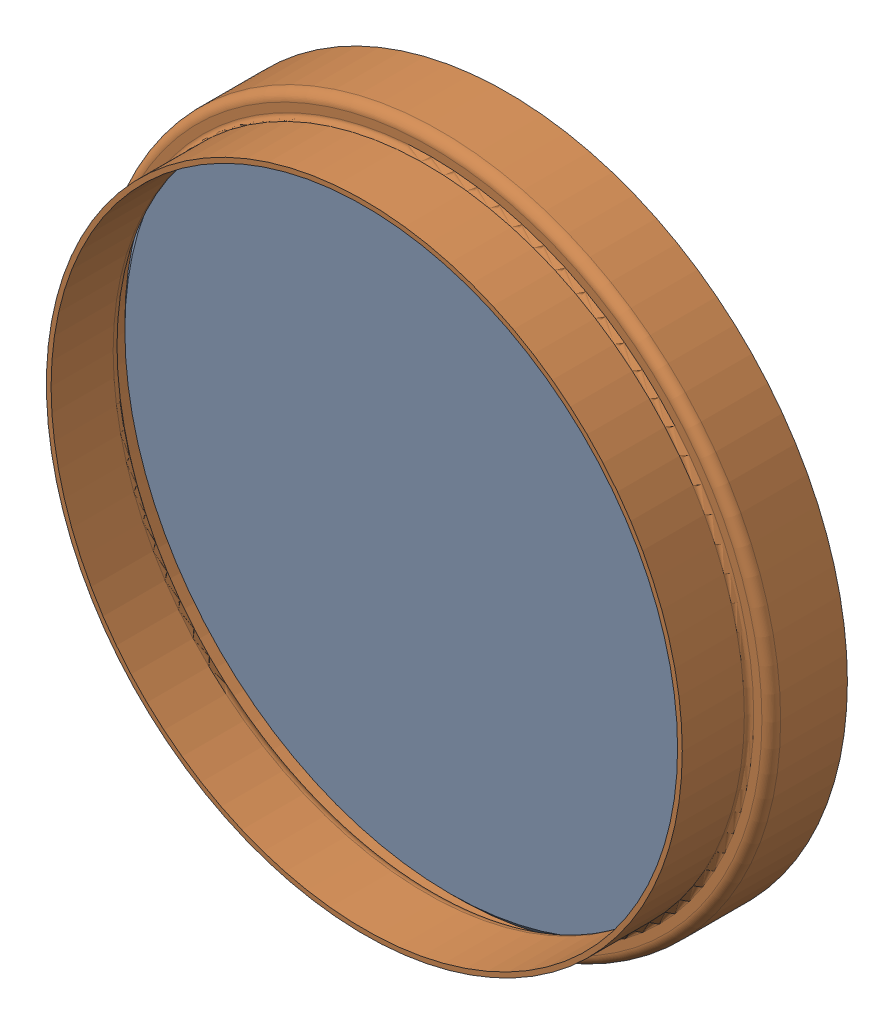
SolidWorks assembly 1004602A, configuration Default. Lengths in mm.
Overall size (73.79 73.79 15.62).
2 component instances, 2 part files, 0 mates.
Components (placement in the parent):
- 1002203A-1: 1002203A [Default] at (0 0 -9.271) x (-1 0 0) z (0 0 -1) size (72.01 72.01 6.35)
- Viewport 4.5 P1_0194302B-1: Viewport 4.5 P1_0194302B [Default] at origin size (73.79 73.79 15.49)
